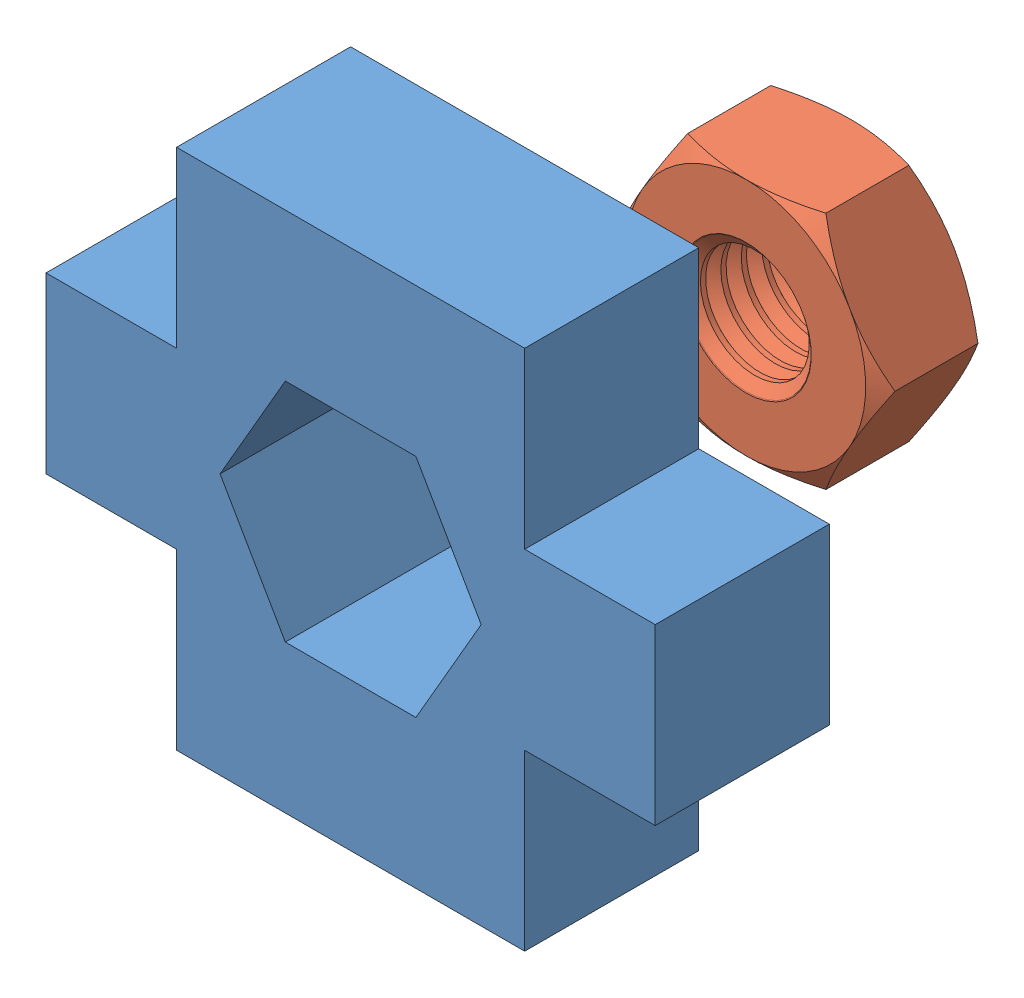
SolidWorks assembly Assem2, configuration Default. Lengths in mm.
Overall size (14 12 11.4).
2 component instances, 2 part files, 3 mates.
Components (placement in the parent):
- BasePulleyInsidePalm-1: BasePulleyInsidePalm [Default] at (3.6005 5.4798 12.8446) size (14 12 4)
- hex nut style 1 gradeab_din-1: hex nut style 1 gradeab_din [Hexagon Nut ISO 4032 - M3 - D - S] at (7.6882 11.6317 7.8446) x (-0.866025 -0.5 0) z (0 0 1) size (5.5 6.35 2.4)
Mates (geometry in assembly coordinates):
- Coincident1: coincident: plane of BasePulleyInsidePalm-1 through (6.1005 8.8817 16.8446) normal (0 1 0); plane of hex nut style 1 gradeab_din-1 through (6.1005 8.8817 5.4446) normal (0 -1 0)
- Coincident2: coincident: plane of BasePulleyInsidePalm-1 through (4.6005 11.4798 16.8446) normal (0.866025 0.5 0); plane of hex nut style 1 gradeab_din-1 through (6.1005 8.8817 5.4446) normal (-0.866025 -0.5 0)
- Distance1: distance = 5 mm anti-aligned: plane of BasePulleyInsidePalm-1 through (3.6005 5.4798 12.8446) normal (0 0 -1); plane of hex nut style 1 gradeab_din-1 through (9.2759 8.8817 7.8446) normal (0 0 1)
